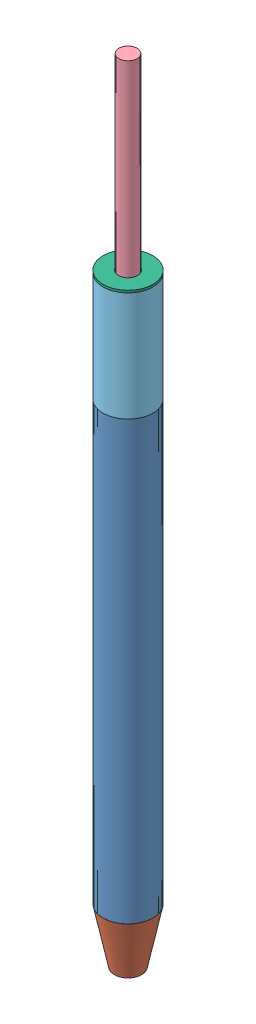
SolidWorks assembly Assembly, configuration Default. Lengths in mm.
Overall size (79.79 1102.9 79.79).
7 component instances, 7 part files, 11 mates.
Components (placement in the parent):
- clear_tube-1: clear_tube [Default] at (-42.8613 -206.2951 162.7712) size (69.32 609.6 69.32)
- tip-1: tip [Default] at (-42.8613 -282.4951 162.7712) x (0.98633 0 -0.164782) z (0.164782 0 0.98633) size (69.32 114.3 69.32)
- inside-1: inside [Default] at (-42.8613 1.4003 162.7712) x (-0.155304 0 0.987867) z (-0.987867 0 -0.155304) size (54.71 635 54.71)
- pusher-1: pusher [Default] at (-42.8613 718.8076 162.7712) x (-0.807689 0 0.589609) z (0.589609 0 0.807689) size (54.71 469.95 55.47)
- upper_tube-1: upper_tube [Default] at (-42.8613 403.3049 162.7712) size (69.32 152.4 69.32)
- upper_cap-1: upper_cap [Default] at (-42.8613 555.7049 162.7712) size (69.32 3.17 69.32)
- spacer-1: spacer [Default] at (-42.8613 -206.2951 162.7712) size (56.08 38.1 56.08)
Mates (geometry in assembly coordinates):
- Concentric1: concentric aligned: cylinder of clear_tube-1 through (-42.8613 403.3049 162.7712) axis (0 -1 0) radius 34.6583; cylinder of tip-1 through (-42.8613 -282.4951 162.7712) axis (0 -1 0) radius 20.6375
- Coincident1: coincident anti-aligned: plane of clear_tube-1 through (-42.8613 -206.2951 162.7712) normal (0 -1 0); plane of tip-1 through (-37.1502 -206.2951 196.9557) normal (0 1 0)
- Concentric2: concentric aligned: cylinder of tip-1 through (-42.8613 -282.4951 162.7712) axis (0 -1 0) radius 13.716; cylinder of inside-1 through (-42.8613 1.4003 162.7712) axis (0 -1 0) radius 12.7
- Concentric3: concentric anti-aligned: cylinder of clear_tube-1 through (-42.8613 403.3049 162.7712) axis (0 -1 0) radius 34.6583; cylinder of pusher-1 through (-42.8613 718.8076 162.7712) axis (0 1 0) radius 27.305
- Coincident2: coincident: line of clear_tube-1 through (-36.5113 276.3049 141.808) axis (0 1 0); plane of pusher-1 through (-39.1795 501.1231 150.6166) normal (-0.957056 0 -0.289904)
- Concentric4: concentric aligned: cylinder of clear_tube-1 through (-42.8613 403.3049 162.7712) axis (0 -1 0) radius 34.6583; cylinder of upper_tube-1 through (-42.8613 555.7049 162.7712) axis (0 -1 0) radius 34.6583
- Coincident3: coincident anti-aligned: circle of clear_tube-1; plane of upper_tube-1 through (-42.8613 403.3049 162.7712) normal (0 -1 0)
- Coincident4: coincident anti-aligned: plane of upper_tube-1 through (-42.8613 555.7049 162.7712) normal (0 1 0); plane of upper_cap-1 through (-42.8613 555.7049 162.7712) normal (0 -1 0)
- Concentric5: concentric aligned: cylinder of upper_tube-1 through (-42.8613 555.7049 162.7712) axis (0 -1 0) radius 34.6583; cylinder of upper_cap-1 through (-42.8613 558.8799 162.7712) axis (0 -1 0) radius 34.6583
- Concentric6: concentric aligned: cylinder of clear_tube-1 through (-42.8613 403.3049 162.7712) axis (0 -1 0) radius 34.6583; cylinder of spacer-1 through (-42.8613 -206.2951 162.7712) axis (0 -1 0) radius 28.0416
- Coincident5: coincident anti-aligned: circle of clear_tube-1; circle of spacer-1
